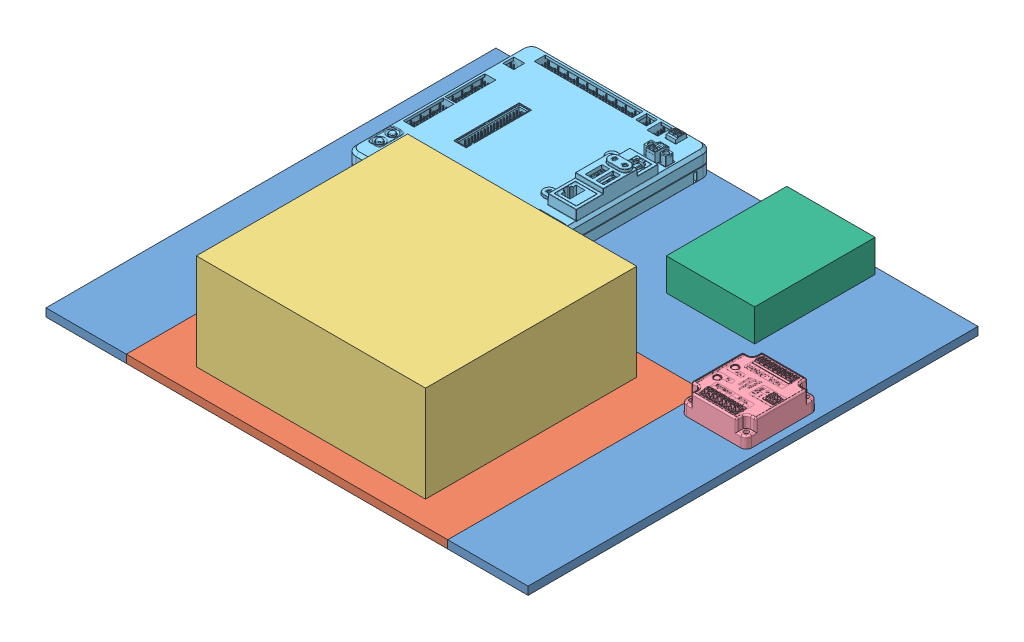
SolidWorks assembly NewFinalAssembly, configuration Default. Lengths in mm.
Overall size (381 82.3 355.6).
7 component instances, 6 part files, 14 mates.
Components (placement in the parent):
- bottom board-1: bottom board [Default] at (-81.1338 205.8751 554.2994) size (381 6.35 355.6)
- battery-1: battery [Default] at (312.8556 80.1479 303.6781) x (0 0 1) z (-1 0 0) size (203.2 82.3 254)
  - batterery board-1: batterery board [Default] at (-26.2387 125.7271 330.4894) size (203.2 6.35 254)
  - Battery-1: Battery [Default] at (-8.9667 208.0231 294.1674) x (0 -1 0) z (0 0 1) size (75.95 166.88 181.1)
- VRM-1: VRM [Default] at (265.9191 219.3564 273.2326) x (0 0 -1) z (1 0 0) size (56.39 19.92 51.56)
- Roborio-2: Roborio [Default] at (20.4459 221.8771 200.165) x (0 0 1) z (0 1 0) size (146.27 143.19 36.83)
- radio b;ock-2: radio b;ock [Default] at (153.8162 212.2251 225.3694) size (69.85 25.4 95.25)
Mates (geometry in assembly coordinates):
- Coincident25: coincident aligned: plane of bottom board-1 through (-81.1338 212.2251 554.2994) normal (0 1 0); plane of Roborio-2 through (-51.5208 212.2251 126.653) normal (0 1 0)
- Coincident29: coincident anti-aligned: plane of bottom board-1 through (-81.1338 212.2251 554.2994) normal (0 1 0); plane of radio b;ock-2 through (153.8162 212.2251 225.3694) normal (0 -1 0)
- Distance3: distance = 76.2 mm aligned: plane of radio b;ock-2 through (223.6662 237.6251 225.3694) normal (1 0 0); plane of bottom board-1 through (299.8662 212.2251 554.2994) normal (1 0 0)
- Distance4: distance = 5.08 mm aligned: plane of radio b;ock-2 through (153.8162 237.6251 130.1194) normal (0 0 -1); plane of bottom board-1 through (-81.1338 212.2251 125.0394) normal (0 0 -1)
- Coincident32: coincident anti-aligned: plane of bottom board-1 through (-81.1338 212.2251 554.2994) normal (0 1 0); plane of VRM-1 through (246.3718 212.2251 249.8882) normal (0 -1 0)
- Perpendicular9: perpendicular: plane of bottom board-1 through (299.8662 212.2251 554.2994) normal (1 0 0); plane of VRM-1 through (246.3718 212.2251 245.5702) normal (0 0.017452 -0.999848)
- Distance5: distance = 12.7 mm aligned: plane of VRM-1 through (287.1662 232.1497 276.8595) normal (1 0 0); plane of bottom board-1 through (299.8662 212.2251 554.2994) normal (1 0 0)
- Coincident39: coincident anti-aligned: plane of bottom board-1 through (-17.6338 205.8751 351.0994) normal (1 0 0); plane of battery-1/batterery board-1 through (-17.6338 212.2251 277.4394) normal (-1 0 0)
- Coincident40: coincident aligned: plane of bottom board-1 through (-81.1338 205.8751 554.2994) normal (0 -1 0); plane of battery-1/batterery board-1 through (-17.6338 205.8751 277.4394) normal (0 -1 0)
- Distance7: distance = 127 mm aligned: plane of VRM-1 through (281.4119 232.1497 252.0394) normal (0 0 -1); plane of bottom board-1 through (-81.1338 212.2251 125.0394) normal (0 0 -1)
- Coincident43: coincident anti-aligned: plane of bottom board-1 through (-81.1338 205.8751 277.4394) normal (0 0 1); plane of battery-1/batterery board-1 through (-17.6338 212.2251 277.4394) normal (0 0 -1)
- Parallel1: parallel anti-aligned: plane of bottom board-1 through (-81.1338 212.2251 554.2994) normal (-1 0 0); plane of Roborio-2 through (83.4678 232.8245 242.1329) normal (1 0 0)
- Distance8: distance = 12.7 mm aligned: plane of Roborio-2 through (-23.6759 232.2445 137.7394) normal (0 0 -1); plane of bottom board-1 through (-81.1338 212.2251 125.0394) normal (0 0 -1)
- Distance9: distance = 38.1 mm aligned: plane of Roborio-2 through (-43.0338 232.2445 207.785) normal (-1 0 0); plane of bottom board-1 through (-81.1338 212.2251 554.2994) normal (-1 0 0)
